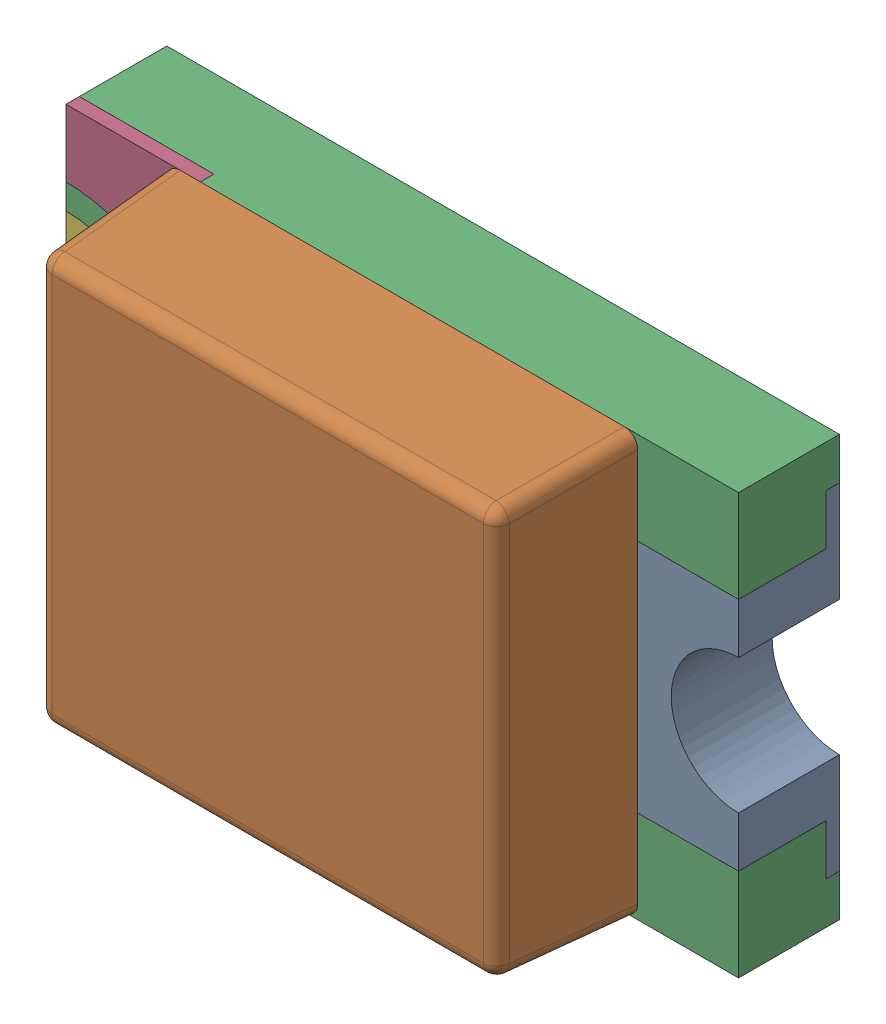
SolidWorks assembly D8, configuration Standard. Lengths in mm.
Overall size (2 1.25 0.7).
7 component instances, 5 part files, 0 mates.
Components (placement in the parent):
- WL-SMCW_0805_LED-1: WL-SMCW_0805_LED [Standard] at (12.1002 18.5002 -0.02) x (1 0 0) z (0 0 1) size (2 1.25 0.7)
  - base-1: base [Standard] at (0.8 0 0) x (-1 0 0) z (0 0 1) size (0.4 1 0.3)
  - cover-1: cover [Standard] at (0 0 0.3) size (1.4 1.25 0.4)
  - housing_3-1: housing_3 [Standard] at origin size (2 1.25 0.3)
  - marking-1: marking [Standard] at (-0.8 0.525 0.26) size (0.4 0.48 0.04)
  - marking-2: marking [Standard] at (-0.8 -0.525 0.3) x (1 0 0) z (0 0 -1) size (0.4 0.48 0.04)
  - base_2-1: base_2 [Standard] at (-0.8 0 0) size (0.4 1 0.3)
